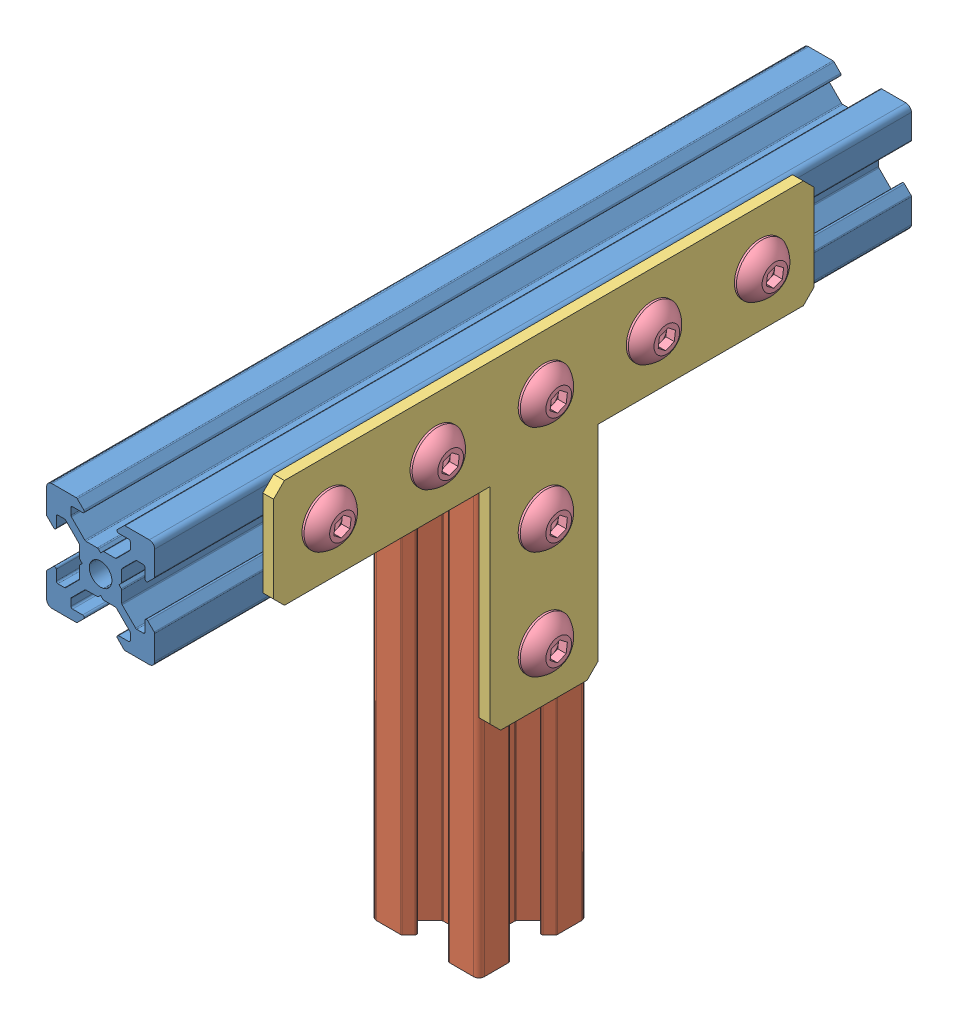
SolidWorks assembly Т-пластина 20 серия 3х5 7отв 60х100х2 СБ, configuration По умолчанию. Lengths in mm.
Overall size (24.75 100 140).
10 component instances, 4 part files, 21 mates.
Components (placement in the parent):
- 2020100-1: 2020100 [По умолчанию] at origin size (20 20 140)
- 202050-2: 202050 [По умолчанию] at (0 -90 70) x (1 0 0) z (0 1 0) size (20 20 80)
- Т-пластина 20 серия 3х5 7отв 60х100х2-1: Т-пластина 20 серия 3х5 7отв 60х100х2 [По умолчанию] at (10 -50 70) x (0 0 -1) z (0 -1 0) size (100 2 60)
- socket button head screw_iso-5: socket button head screw_iso [ISO 7380 - M5 x 10 - 10N] at (14.75 0 90) x (-1 0 0) z (0 0.924225 0.381849) size (12.75 9.5 9.5)
- socket button head screw_iso-6: socket button head screw_iso [ISO 7380 - M5 x 10 - 10N] at (14.75 0 50) x (-1 0 0) z (0 0.924225 0.381849) size (12.75 9.5 9.5)
- socket button head screw_iso-7: socket button head screw_iso [ISO 7380 - M5 x 10 - 10N] at (14.75 -20 70) x (-1 0 0) z (0 0.924225 0.381849) size (12.75 9.5 9.5)
- socket button head screw_iso-8: socket button head screw_iso [ISO 7380 - M5 x 10 - 10N] at (14.75 -40 70) x (-1 0 0) z (0 0.924225 0.381849) size (12.75 9.5 9.5)
- socket button head screw_iso-9: socket button head screw_iso [ISO 7380 - M5 x 10 - 10N] at (14.75 0 30) x (-1 0 0) z (0 0.924225 0.381849) size (12.75 9.5 9.5)
- socket button head screw_iso-10: socket button head screw_iso [ISO 7380 - M5 x 10 - 10N] at (14.75 0 70) x (-1 0 0) z (0 0.924225 0.381849) size (12.75 9.5 9.5)
- socket button head screw_iso-11: socket button head screw_iso [ISO 7380 - M5 x 10 - 10N] at (14.75 0 110) x (-1 0 0) z (0 0.924225 0.381849) size (12.75 9.5 9.5)
Mates (geometry in assembly coordinates):
- Совпадение1: coincident aligned: plane of 2020100-1 through (10 -10 140) normal (1 0 0); plane of 202050-2 through (10 -10 60) normal (1 0 0)
- Совпадение2: coincident anti-aligned: plane of 2020100-1 through (10 -10 140) normal (0 -1 0); plane of 202050-2 through (0 -10 70) normal (0 1 0)
- Совпадение3: coincident anti-aligned: plane of 2020100-1 through (10 -10 140) normal (1 0 0); plane of Т-пластина 20 серия 3х5 7отв 60х100х2-1 through (10 -50 70) normal (-1 0 0)
- Совпадение4: coincident aligned: plane of 2020100-1 through (10 10 140) normal (0 1 0); plane of Т-пластина 20 серия 3х5 7отв 60х100х2-1 through (12 10 120) normal (0 1 0)
- Концентричный1: concentric aligned: cylinder of Т-пластина 20 серия 3х5 7отв 60х100х2-1 through (12 0 90) axis (1 0 0) radius 2.75; cylinder of socket button head screw_iso-5 through (14.75 0 90) axis (1 0 0) radius 4.75
- Совпадение6: coincident anti-aligned: plane of Т-пластина 20 серия 3х5 7отв 60х100х2-1 through (12 -50 70) normal (1 0 0); plane of socket button head screw_iso-5 through (12 -0.9546 92.3106) normal (-1 0 0)
- Концентричный2: concentric aligned: cylinder of Т-пластина 20 серия 3х5 7отв 60х100х2-1 through (12 0 50) axis (1 0 0) radius 2.75; cylinder of socket button head screw_iso-6 through (14.75 0 50) axis (1 0 0) radius 4.75
- Совпадение7: coincident anti-aligned: plane of Т-пластина 20 серия 3х5 7отв 60х100х2-1 through (12 -50 70) normal (1 0 0); plane of socket button head screw_iso-6 through (12 -0.9546 52.3106) normal (-1 0 0)
- Концентричный3: concentric aligned: cylinder of Т-пластина 20 серия 3х5 7отв 60х100х2-1 through (12 -20 70) axis (1 0 0) radius 2.75; cylinder of socket button head screw_iso-7 through (14.75 -20 70) axis (1 0 0) radius 4.75
- Совпадение8: coincident anti-aligned: plane of Т-пластина 20 серия 3х5 7отв 60х100х2-1 through (12 -50 70) normal (1 0 0); plane of socket button head screw_iso-7 through (12 -20.9546 72.3106) normal (-1 0 0)
- Концентричный4: concentric aligned: cylinder of Т-пластина 20 серия 3х5 7отв 60х100х2-1 through (12 -40 70) axis (1 0 0) radius 2.75; cylinder of socket button head screw_iso-8 through (14.75 -40 70) axis (1 0 0) radius 4.75
- Совпадение9: coincident anti-aligned: plane of Т-пластина 20 серия 3х5 7отв 60х100х2-1 through (12 -50 70) normal (1 0 0); plane of socket button head screw_iso-8 through (12 -40.9546 72.3106) normal (-1 0 0)
- Расстояние1: distance = 20 mm aligned: plane of Т-пластина 20 серия 3х5 7отв 60х100х2-1 through (12 10 120) normal (0 0 1); plane of 2020100-1 through (0 0 140) normal (0 0 1)
- Совпадение11: coincident aligned: plane of 202050-2 through (10 -10 80) normal (0 0 1); plane of Т-пластина 20 серия 3х5 7отв 60х100х2-1 through (12 -10 80) normal (0 0 1)
- Совпадение12: coincident aligned: plane of 202050-2 through (10 -10 80) normal (0 0 1); plane of Т-пластина 20 серия 3х5 7отв 60х100х2-1 through (12 -10 80) normal (0 0 1)
- Концентричный5: concentric aligned: cylinder of Т-пластина 20 серия 3х5 7отв 60х100х2-1 through (12 0 30) axis (1 0 0) radius 2.75; cylinder of socket button head screw_iso-9 through (14.75 0 30) axis (1 0 0) radius 4.75
- Совпадение13: coincident anti-aligned: plane of Т-пластина 20 серия 3х5 7отв 60х100х2-1 through (12 -50 70) normal (1 0 0); plane of socket button head screw_iso-9 through (12 -0.9546 32.3106) normal (-1 0 0)
- Концентричный6: concentric aligned: cylinder of Т-пластина 20 серия 3х5 7отв 60х100х2-1 through (12 0 70) axis (1 0 0) radius 2.75; cylinder of socket button head screw_iso-10 through (14.75 0 70) axis (1 0 0) radius 4.75
- Совпадение14: coincident anti-aligned: plane of Т-пластина 20 серия 3х5 7отв 60х100х2-1 through (12 -50 70) normal (1 0 0); plane of socket button head screw_iso-10 through (12 -0.9546 72.3106) normal (-1 0 0)
- Концентричный7: concentric aligned: cylinder of Т-пластина 20 серия 3х5 7отв 60х100х2-1 through (12 0 110) axis (1 0 0) radius 2.75; cylinder of socket button head screw_iso-11 through (14.75 0 110) axis (1 0 0) radius 4.75
- Совпадение15: coincident anti-aligned: plane of Т-пластина 20 серия 3х5 7отв 60х100х2-1 through (12 -50 70) normal (1 0 0); plane of socket button head screw_iso-11 through (12 -0.9546 112.3106) normal (-1 0 0)
